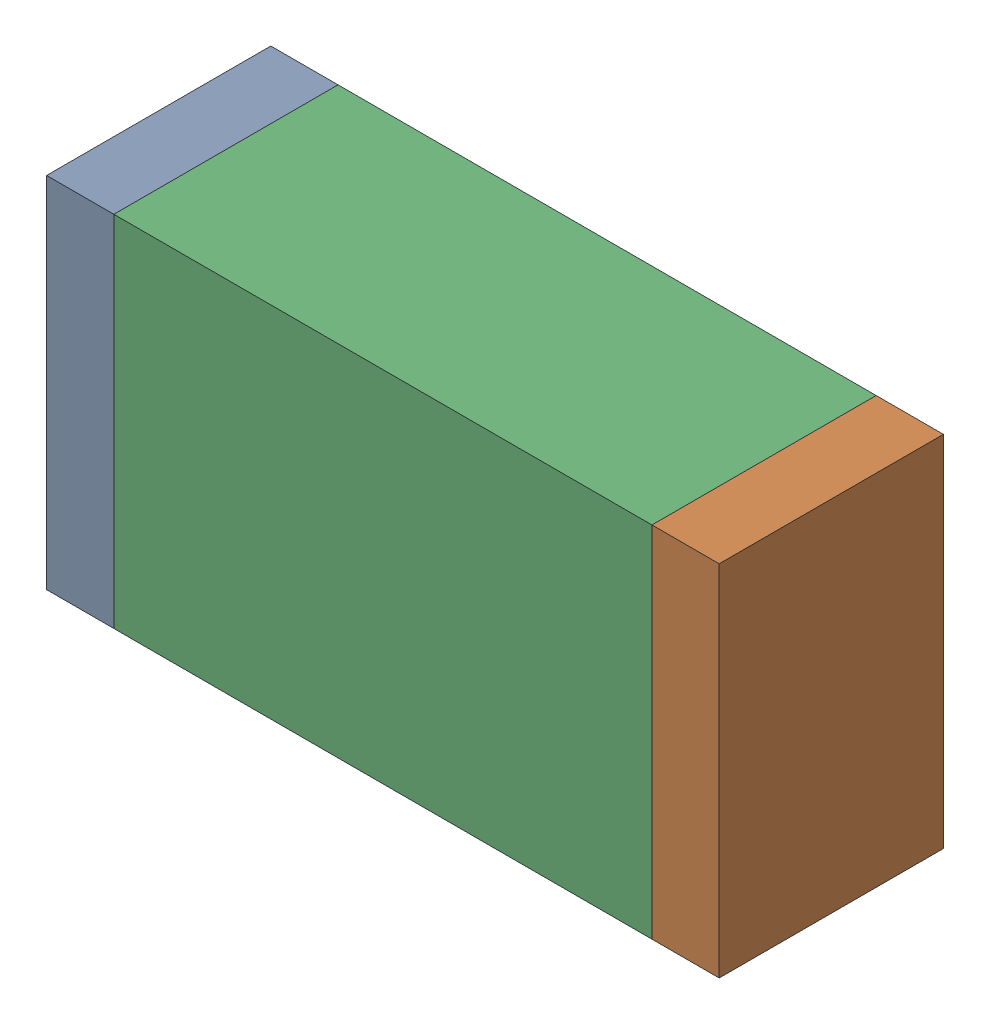
SolidWorks assembly R33, configuration Default. Lengths in mm.
Overall size (1.5 0.8 0.5).
6 component instances, 2 part files, 0 mates.
Components (placement in the parent):
- 836752496-1: 836752496 [Default] at (120.725 49.3 0) size (0.15 0.8 0.5)
  - Extruded_2-1: Extruded_2 [Default] at origin size (0.15 0.8 0.5)
- 836752496-2: 836752496 [Default] at (122.075 49.3 0) size (0.15 0.8 0.5)
  - Extruded_2-1: Extruded_2 [Default] at origin size (0.15 0.8 0.5)
- 836752368-1: 836752368 [Default] at (121.4 49.3 0) size (1.2 0.8 0.5)
  - Extruded-1: Extruded [Default] at origin size (1.2 0.8 0.5)
